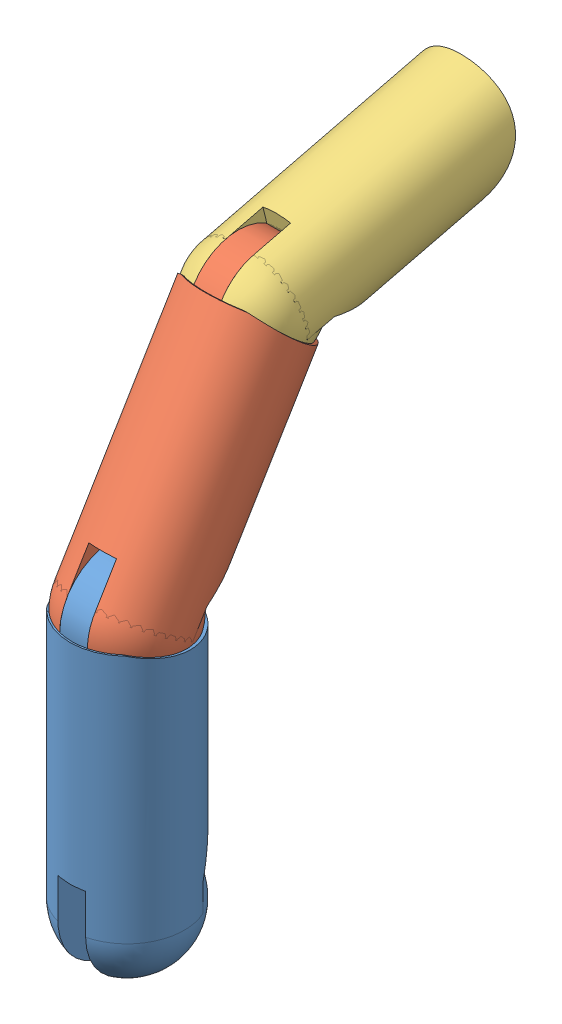
SolidWorks assembly ensamblajefinal, configuration Predeterminado. Lengths in mm.
Overall size (16.5 89.53 63.45).
3 component instances, 3 part files, 4 mates.
Components (placement in the parent):
- anular-1: anular [Predeterminado] at (0.3971 -19.6954 52.4039) size (16.5 51.75 16.5)
- anular2-1: anular2 [Predeterminado] at (0.3971 16.3046 52.4039) x (1 0 0) z (0 0.515849 0.856679) size (16 50.25 16)
- anular3-1: anular3 [Predeterminado] at (0.3971 46.2884 34.3492) x (1 0 0) z (0 0.971218 0.238191) size (15.5 41.15 15.5)
Mates (geometry in assembly coordinates):
- Coincidente1: coincident anti-aligned: plane of anular-1 through (2.3971 16.3046 52.4039) normal (1 0 0); plane of anular2-1 through (2.3971 13.7069 36.4586) normal (-1 0 0)
- Concéntrica1: concentric: sphere of anular-1; sphere of anular2-1
- Coincidente2: coincident anti-aligned: plane of anular2-1 through (2.3971 46.2884 34.3492) normal (1 0 0); plane of anular3-1 through (2.3971 34.5516 40.2226) normal (-1 0 0)
- Concéntrica2: concentric: sphere of anular2-1; sphere of anular3-1
